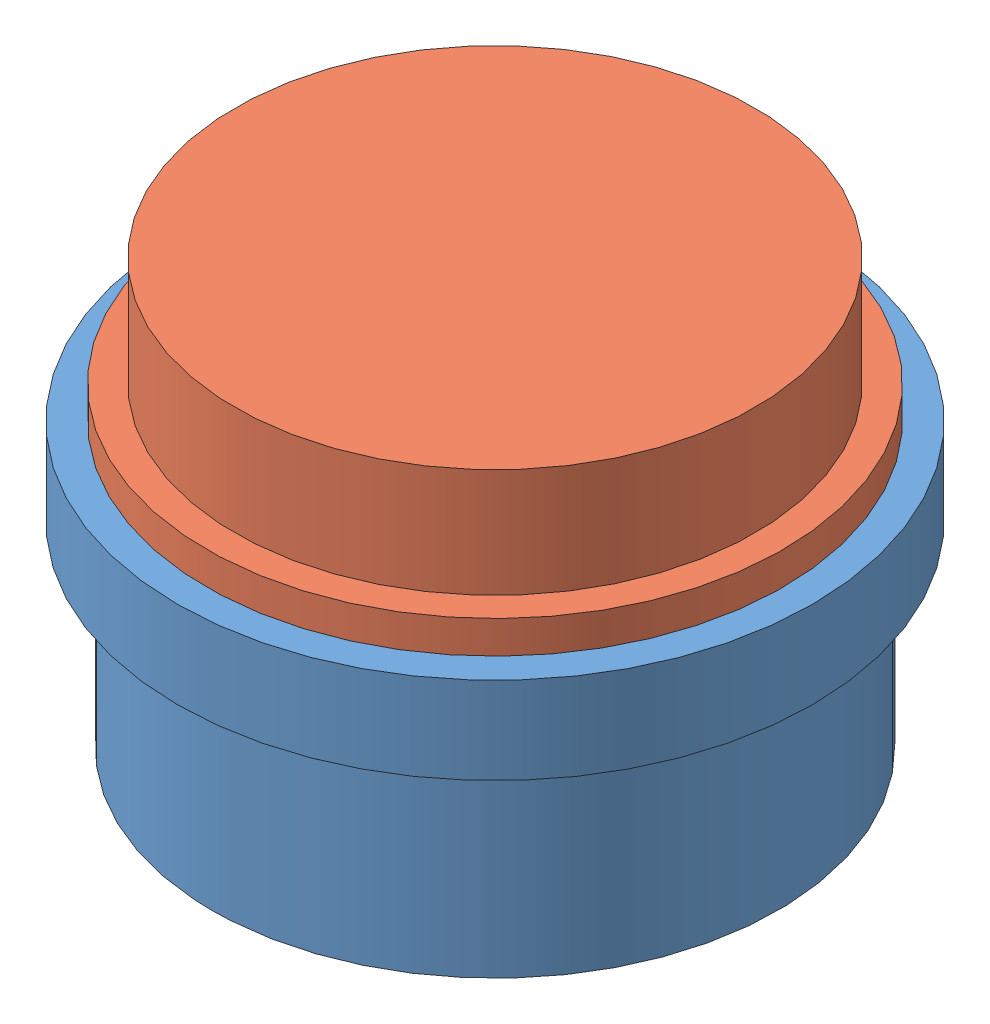
SolidWorks assembly O2, configuration Default. Lengths in mm.
Overall size (73.42 40 73.42).
2 component instances, 2 part files, 0 mates.
Components (placement in the parent):
- O2Screw-1: O2Screw [Default] at (16.5159 33.1382 43.7946) size (58.41 26 58.41)
- R-30VSLDPRT-1: R-30VSLDPRT [Default] at (16.5159 32.1382 43.7946) x (0.834767 0 0.550604) z (-0.550604 0 0.834767) size (53 40 53)
